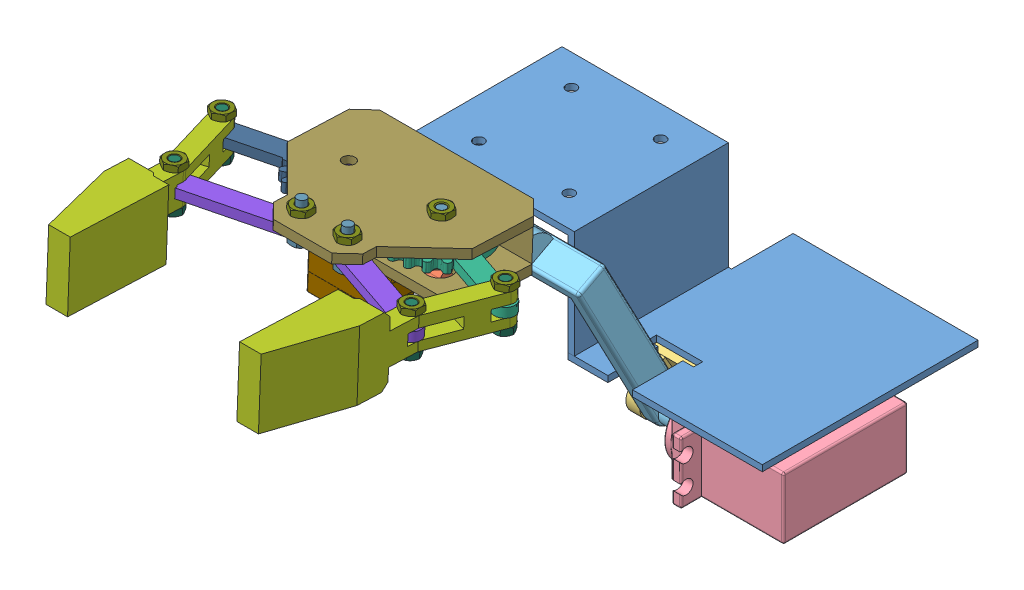
SolidWorks assembly Assem3, configuration Default. Lengths in mm.
Overall size (142.46 166.43 202.05).
32 component instances, 17 part files, 7 mates.
Components (placement in the parent):
- Base-1: Base [Default] at (127.5084 -19.7377 87.1974) size (130 49.99 70.01)
- joint-1: joint [Default] at (35.8214 -26.2329 92.7019) x (0 -0.866025 -0.5) z (-1 0 0) size (15 15 15)
- joint-half-1: joint-half [Default] at (97.1971 -26.2329 92.7019) x (0 0.866025 0.5) z (1 0 0) size (15 15 15)
- Servo MG996R-1: Servo MG996R [Predeterminado] at (153.349 -21.2329 111.3621) x (0 0 -1) z (0 1 0) size (53.6 47.6 20)
- arm1-1: arm1 [Default] at (128.0479 7.6553 52.8151) x (1 0 0) z (0 -0.885193 -0.465225) size (110.02 107.88 131.32)
  - arm-2: arm [Default] at (-24.8916 55.9585 30.1716) size (87 10 66.93)
  - Assembly 2.0 upload.stp-2: Assembly 2.0 upload.stp [Default] at (-62.3508 78.3564 -62.8111) x (0 -0.866025 0.5) z (-1 0 0) size (99.56 43.3 110.02)
    - gear.stp-1: gear.stp [Default] at (1.3043 -4.9957 -15) x (0.330984 0 0.943636) z (-0.943636 0 0.330984) size (53 3 32)
    - gripper.stp-1: gripper.stp [Default] at (-7.3079 -8.4957 47.6327) size (71 22 21.5)
    - tuas.stp-1: tuas.stp [Default] at (-30.3079 -1.9957 40.1327) x (-0.966894 0 -0.255178) z (-0.255178 0 0.966894) size (6.5 3 40.25)
    - gripper.stp-2: gripper.stp [Default] at (-9.8664 1.0043 -46.8477) x (1 0 0) z (0 0 -1) size (71 22 21.5)
    - tuas.stp-2: tuas.stp [Default] at (-32.8664 -1.9957 -39.3477) x (0.943636 0 -0.330984) z (-0.330984 0 -0.943636) size (6.5 3 40.25)
    - microservoSG90.stp-1: microservoSG90.stp [Default] at (1.3043 28.3043 9.9) x (0 0 -1) z (-1 0 0) size (32.3 29.8 12.41)
    - gear 2.1.stp-1: gear 2.1.stp [Default] at (1.3043 -1.9957 15) x (0.255178 0 -0.966894) z (-0.966894 0 -0.255178) size (52.85 3 31.7)
    - servo horn 1 v2.stp-1: servo horn 1 v2.stp [Default] at (1.3043 -1.4957 15) x (-0.966894 0 -0.255178) z (-0.255178 0 0.966894) size (7.2 3.7 21.2)
    - base 2.0 upload.stp-1: base 2.0 upload.stp [Default] at (28.3043 -7.9957 35) size (50 18.1 60)
    - Gear Ring.stp-1: Gear Ring.stp [Default] at (1.3043 -1.7957 -15) x (-0.620589 0 -0.784136) z (0.784136 0 -0.620589) size (18 2 18)
    - AS 1427 - M3 x 10.stp-1: AS 1427 - M3 x 10.stp [Default] at (1.3043 0.2043 -15) x (0 -1 0) z (0 0 1) size (12.33 5.5 6.35)
    - AS 1427 - M3 x 10.stp-2: AS 1427 - M3 x 10.stp [Default] at (-21.6957 -1.9957 -7.5) x (0 -1 0) z (0 0 1) size (12.33 5.5 6.35)
    - AS 1427 - M3 x 10.stp-3: AS 1427 - M3 x 10.stp [Default] at (-21.6957 -1.9957 7.5) x (0 -1 0) z (0 0 1) size (12.33 5.5 6.35)
    - AS 1427 - M3 x 12.stp-1: AS 1427 - M3 x 12.stp [Default] at (-9.8664 1.0043 -46.8477) x (0 -1 0) z (0 0 1) size (14.33 5.5 6.35)
    - AS 1427 - M3 x 12.stp-2: AS 1427 - M3 x 12.stp [Default] at (-32.8664 1.0043 -39.3477) x (0 -1 0) z (0 0 1) size (14.33 5.5 6.35)
    - AS 1427 - M3 x 12.stp-3: AS 1427 - M3 x 12.stp [Default] at (-7.3079 1.5043 47.6327) x (0 -1 0) z (0 0 1) size (14.33 5.5 6.35)
    - AS 1427 - M3 x 12.stp-4: AS 1427 - M3 x 12.stp [Default] at (-30.3079 1.5043 40.1327) x (0 -1 0) z (0 0 1) size (14.33 5.5 6.35)
    - AS 1112 - M3,5.stp-1: AS 1112 - M3,5.stp [Default] at (1.3043 -10.0957 -15) x (0 1 0) z (0 0 1) size (2.1 6.93 6)
    - AS 1112 - M3,5.stp-2: AS 1112 - M3,5.stp [Default] at (-21.6957 -10.0957 -7.5) x (0 1 0) z (0 0 1) size (2.1 6.93 6)
    - AS 1112 - M3,5.stp-3: AS 1112 - M3,5.stp [Default] at (-21.6957 -10.0957 7.5) x (0 1 0) z (0 0 1) size (2.1 6.93 6)
    - AS 1112 - M3,5.stp-4: AS 1112 - M3,5.stp [Default] at (-32.8664 -11.0957 -39.3477) x (0 1 0) z (0 0 1) size (2.1 6.93 6)
    - AS 1112 - M3,5.stp-5: AS 1112 - M3,5.stp [Default] at (-9.8664 -11.0957 -46.8477) x (0 1 0) z (0 0 1) size (2.1 6.93 6)
    - AS 1112 - M3,5.stp-6: AS 1112 - M3,5.stp [Default] at (-30.3079 -10.5957 40.1327) x (0 1 0) z (0 0 1) size (2.1 6.93 6)
    - AS 1112 - M3,5.stp-7: AS 1112 - M3,5.stp [Default] at (-7.3079 -10.5957 47.6327) x (0 1 0) z (0 0 1) size (2.1 6.93 6)
    - ISO 7046-1 - M1,6 x 8 - 4.8 - H.stp-1: ISO 7046-1 - M1,6 x 8 - 4.8 - H.stp [Default] at (1.3043 -5.9957 15) x (0 1 0) z (0 0 1) size (8 3 3)
Mates (geometry in assembly coordinates):
- Coincident1: coincident aligned: line of Base-1 through (20.8214 -32.7281 88.9519) axis (0 0.866025 0.5); line of joint-1 through (20.8214 -32.7281 88.9519) axis (0 0.866025 0.5)
- Coincident2: coincident anti-aligned: line of Base-1 through (35.8214 -32.7281 88.9519) axis (-1 0 0); line of joint-1 through (20.8214 -32.7281 88.9519) axis (1 0 0)
- Coincident3: coincident aligned: line of Base-1 through (97.1971 -32.7281 88.9519) axis (1 0 0); line of joint-half-1 through (97.1971 -32.7281 88.9519) axis (1 0 0)
- Coincident4: coincident anti-aligned: line of Base-1 through (112.1971 -32.7281 88.9519) axis (0 0.866025 0.5); line of joint-half-1 through (112.1971 -19.7377 96.4519) axis (0 -0.866025 -0.5)
- Parallel1: parallel anti-aligned: line of Base-1 through (150.8093 -19.7377 45.7219) axis (0 0 1); line of Servo MG996R-1 through (152.749 -21.2329 110.7621) axis (0 0 -1)
- Coincident12: coincident anti-aligned: plane of joint-half-1 through (101.6971 -31.2329 101.3621) normal (1 0 0); plane of arm1-1/arm-2 through (101.6971 10.9685 129.0696) normal (-1 0 0)
- Coincident13: coincident aligned: circle of joint-half-1; circle of arm1-1/arm-2
